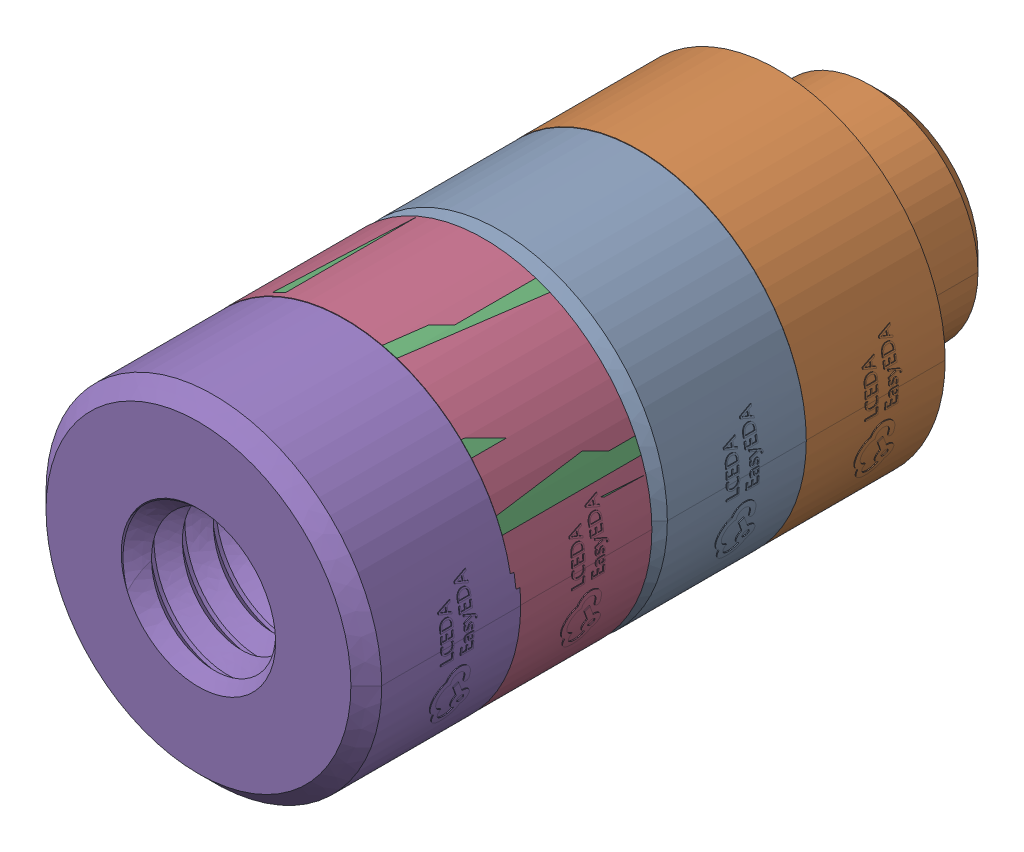
SolidWorks assembly Hole3, configuration Défaut. Lengths in mm.
Overall size (4.36 4.35 8.92).
5 component instances, 1 part files, 0 mates.
Components (placement in the parent):
- SMTWE2055MTJ-1: SMTWE2055MTJ [Défaut] at (8.2005 -43.9084 0.2) x (1 0 0) z (0 0 1) size (4.36 4.35 3.42)
- SMTWE2055MTJ-2: SMTWE2055MTJ [Défaut] at (8.2 -43.9045 -1.6) x (1 0 0) z (0 0 1) size (4.36 4.35 3.42)
- SMTWE2055MTJ-3: SMTWE2055MTJ [Défaut] at (8.2 -43.9045 2.2) x (1 0 0) z (0 0 1) size (4.36 4.35 3.42)
- SMTWE2055MTJ-4: SMTWE2055MTJ [Défaut] at (8.2 -43.9045 2.2) x (1 0 0) z (0 0 1) size (4.36 4.35 3.42)
- SMTWE2055MTJ-5: SMTWE2055MTJ [Défaut] at (8.2005 -43.9084 3.9) x (1 0 0) z (0 0 1) size (4.36 4.35 3.42)
